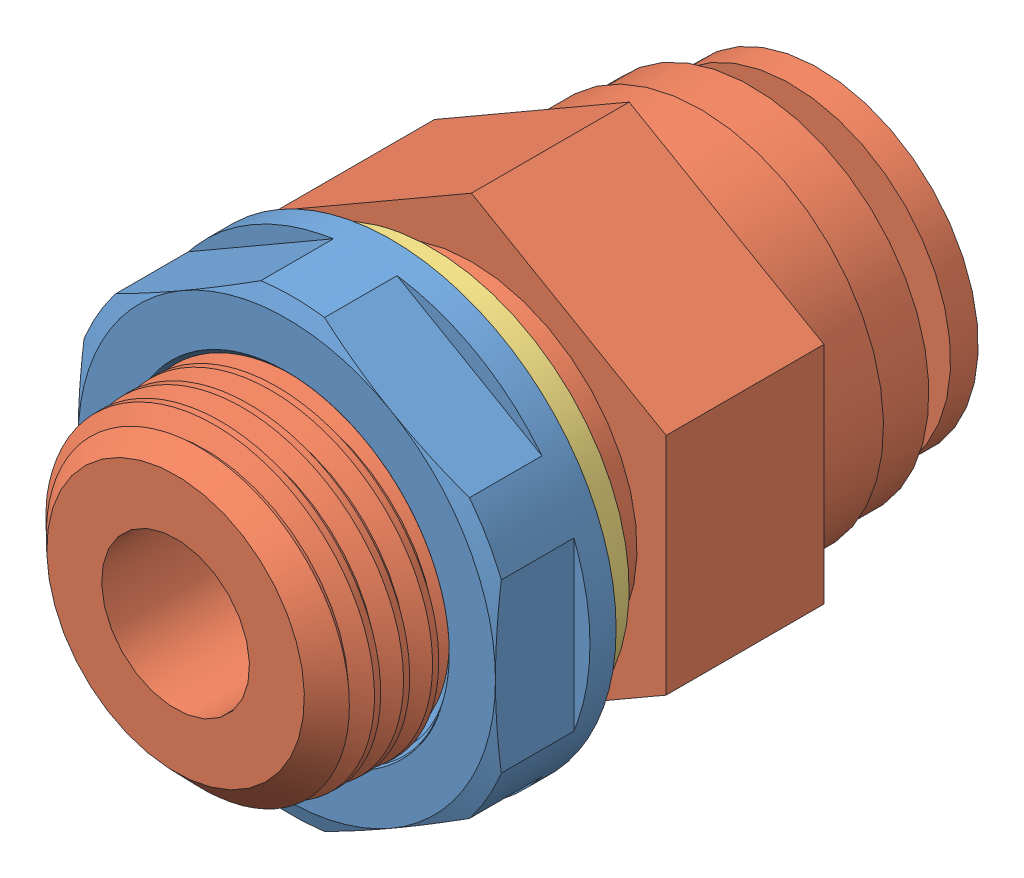
SolidWorks assembly straight_assembly, configuration Default. Lengths in mm.
Overall size (37.62 36.2 41.4).
3 component instances, 3 part files, 5 mates.
Components (placement in the parent):
- true_npt_nut-1: true_npt_nut [3185K112] at (-78.6901 -4.206 40.9866) size (28.95 28.95 10.31)
- through-wall-black-1: through-wall-black [Default] at (-78.6901 -4.206 35.8304) x (0.866025 0.5 0) z (-0.5 0.866025 0) size (28.96 41.4 25.08)
- hrd-050-gasket-1: hrd-050-gasket [Default] at (-78.6901 -4.206 40.9866) x (0.974895 0.222665 0) z (-0.222665 0.974895 0) size (25.4 2.62 25.4)
Mates (geometry in assembly coordinates):
- Concentric1: concentric anti-aligned: circle of through-wall-black-1; circle of hrd-050-gasket-1
- Distance1: distance = 2.54 mm anti-aligned: plane of hrd-050-gasket-1 through (-78.6901 -4.206 38.3704) normal (0 0 -1); plane of through-wall-black-1 through (-78.6901 -4.206 35.8304) normal (0 0 1)
- Concentric2: concentric anti-aligned: circle of true_npt_nut-1; circle of hrd-050-gasket-1
- Coincident2: coincident anti-aligned: plane of true_npt_nut-1 through (-78.6901 11.3093 40.9866) normal (0 0 -1); plane of hrd-050-gasket-1 through (-78.6901 -4.206 40.9866) normal (0 0 1)
- Parallel1: parallel aligned: plane of true_npt_nut-1 through (-65.2535 3.5517 47.7176) normal (0.5 0.866025 0); plane of through-wall-black-1 through (-78.6901 10.2754 25.6704) normal (0.5 0.866025 0)
